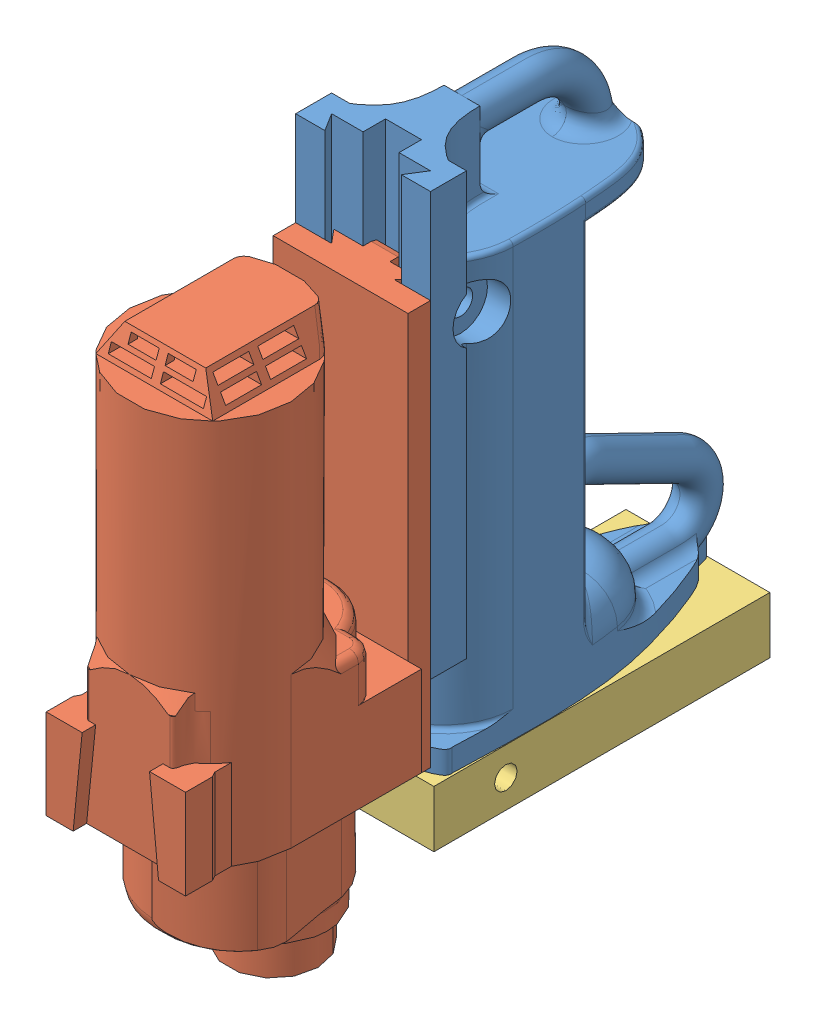
SolidWorks assembly Drill Assembly.11.2.2020, configuration Default. Lengths in mm.
Overall size (114.3 450.85 424.08).
3 component instances, 3 part files, 6 mates.
Components (placement in the parent):
- DrillPressRough-1: DrillPressRough [Default] at (-258.418 -108.7256 676.7697) x (1 0 0) z (0 1 0) size (106.85 250.99 361.95)
- Motor-1: Motor [Default] at (-0.824 -197.6256 394.7148) x (-1 0 0) z (0 -1 0) size (114.3 193.67 403.23)
- DrillMounting-1: DrillMounting [Default] at (-0.824 -108.7256 312.1374) size (105.06 40 237.28)
Mates (geometry in assembly coordinates):
- Coincident3: coincident aligned: plane of DrillPressRough-1 through (46.801 -193.2665 305.8148) normal (1 0 0); plane of Motor-1 through (46.801 -99.2006 394.7148) normal (1 0 0)
- Coincident4: coincident anti-aligned: plane of DrillPressRough-1 through (46.801 -193.2665 331.2148) normal (0 0 1); plane of Motor-1 through (-0.824 -99.2006 331.2148) normal (0 0 -1)
- Coincident6: coincident anti-aligned: plane of DrillPressRough-1 through (-258.418 -108.7256 676.7697) normal (0 -1 0); plane of DrillMounting-1 through (-0.824 -108.7256 312.1374) normal (0 1 0)
- Coincident7: coincident: plane of DrillPressRough-1 through (-258.418 -92.8506 324.8648) normal (0 0 1); line of DrillMounting-1 through (9.7474 -108.7256 324.8648) axis (-1 0 0)
- Tangent1: tangent: curve of DrillPressRough-1; curve of DrillMounting-1
- Distance2: distance = 88.9 mm aligned: plane of Motor-1 through (-0.824 -197.6256 394.7148) normal (0 -1 0); plane of DrillPressRough-1 through (-258.418 -108.7256 676.7697) normal (0 -1 0)
